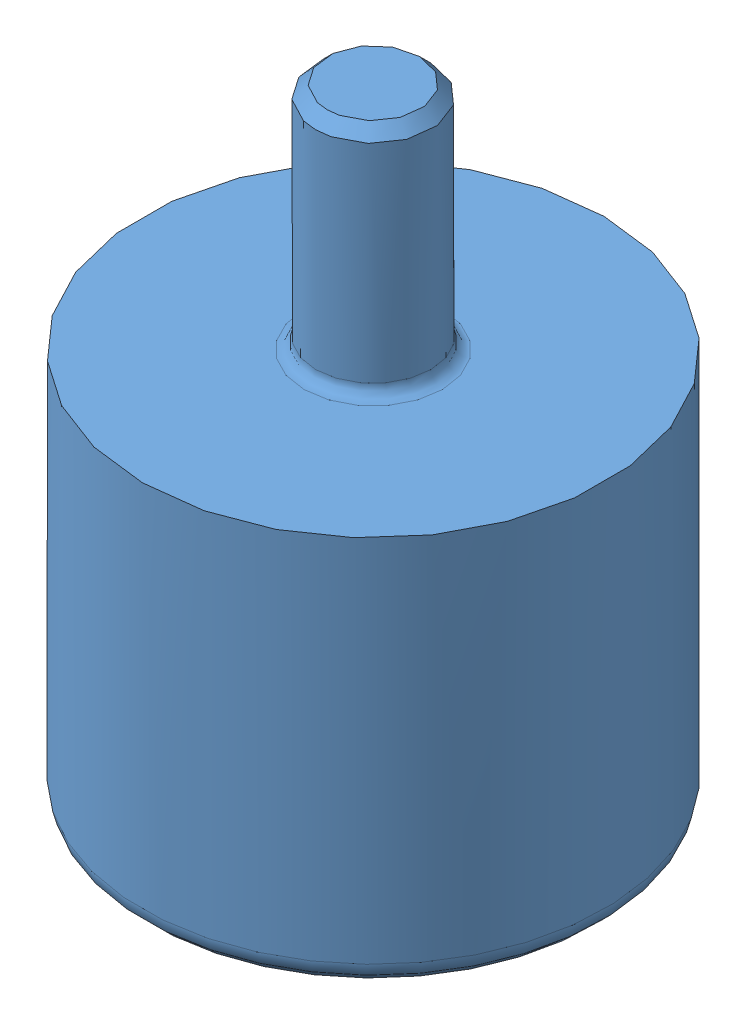
SolidWorks assembly Roulette à bille 687-679-modifiée, configuration Default. Lengths in mm.
Overall size (20 33.32 20).
2 component instances, 2 part files, 1 mates.
Components (placement in the parent):
- Roulette D20-1: Roulette D20 [Default] at (-2.1367 -5.4811 4.8512) size (20 27 20)
- bille D12_5-1: bille D12_5 [Default] at (-2.1367 -2.2311 4.8512) x (0.99126 0.131446 -0.011192) z (0.096002 -0.660576 0.744596) size (12.5 12.5 12.5)
Mates (geometry in assembly coordinates):
- Coaxiale1: concentric: sphere of Roulette D20-1; sphere of bille D12_5-1
